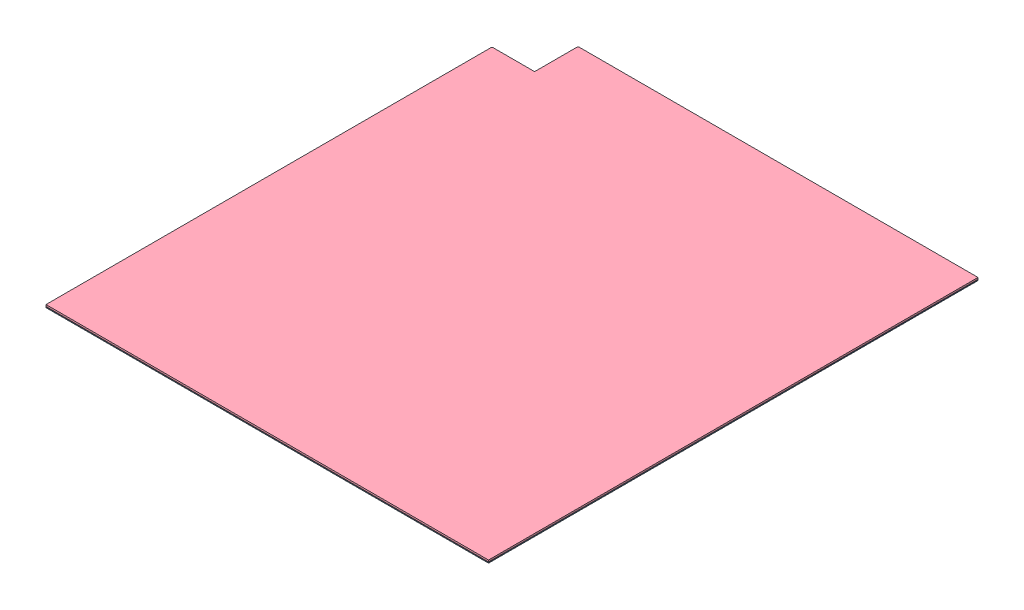
SolidWorks assembly GE-20057, configuration Default. Lengths in mm.
Overall size (1616.07 10.06 1787.53).
7 component instances, 5 part files, 18 mates.
Components (placement in the parent):
- GE-20055-1: GE-20055 [Default] at origin size (1616.07 2.92 593.72)
- Carpet Tape _ 63.625-1: Carpet Tape _ 63.625 [Default] at (808.0375 2.921 -25.4) x (0 0 1) z (-1 0 0) size (50.8 0.79 1616.07)
- Carpet Tape _ 57.375-1: Carpet Tape _ 57.375 [Default] at (887.4125 2.921 -568.325) x (0 0 1) z (-1 0 0) size (50.8 0.79 1457.33)
- GE-20057 - 01-1: GE-20057 - 01 [Default] at (0 3.7147 1193.8) size (1616.07 6.35 1787.53)
- GE-20056-1: GE-20056 [Default] at (0 0 1193.8) size (1616.07 2.92 1193.8)
- Carpet Tape _ 63.625-2: Carpet Tape _ 63.625 [Default] at (808.0375 2.921 25.4) x (0 0 -1) z (1 0 0) size (50.8 0.79 1616.07)
- Carpet Tape _ 63.625-4: Carpet Tape _ 63.625 [Default] at (808.0375 2.921 1168.4) x (0 0 1) z (-1 0 0) size (50.8 0.79 1616.07)
Mates (geometry in assembly coordinates):
- Coincident1: coincident anti-aligned: plane of GE-20055-1 through (3.175 2.921 -431.8) normal (0 1 0); plane of Carpet Tape _ 63.625-1 through (808.0375 2.921 -25.4) normal (0 -1 0)
- Coincident2: coincident aligned: plane of GE-20055-1 through (0 2.921 0) normal (0 0 1); plane of Carpet Tape _ 63.625-1 through (1616.075 3.7147 0) normal (0 0 1)
- Coincident3: coincident aligned: plane of GE-20055-1 through (1616.075 2.921 0) normal (1 0 0); plane of Carpet Tape _ 63.625-1 through (1616.075 3.7147 -50.8) normal (1 0 0)
- Coincident4: coincident anti-aligned: plane of GE-20055-1 through (3.175 2.921 -431.8) normal (0 1 0); plane of Carpet Tape _ 57.375-1 through (887.4125 2.921 -568.325) normal (0 -1 0)
- Coincident5: coincident aligned: plane of GE-20055-1 through (158.75 2.921 -593.725) normal (0 0 -1); plane of Carpet Tape _ 57.375-1 through (1616.075 3.7147 -593.725) normal (0 0 -1)
- Coincident6: coincident: line of GE-20055-1 through (158.75 2.921 -593.725) axis (0 -1 0); plane of Carpet Tape _ 57.375-1 through (158.75 3.7147 -593.725) normal (-1 0 0)
- Coincident7: coincident anti-aligned: plane of Carpet Tape _ 57.375-1 through (887.4125 3.7147 -568.325) normal (0 1 0); plane of GE-20057 - 01-1 through (3.175 3.7147 -1625.6) normal (0 -1 0)
- Coincident8: coincident aligned: plane of GE-20055-1 through (0 2.921 0) normal (-1 0 0); plane of GE-20057 - 01-1 through (0 10.0648 0) normal (-1 0 0)
- Coincident9: coincident aligned: plane of GE-20056-1 through (0 2.921 1193.8) normal (0 0 1); plane of GE-20057 - 01-1 through (0 10.0648 1193.8) normal (0 0 1)
- Coincident10: coincident aligned: plane of GE-20055-1 through (0 2.921 0) normal (-1 0 0); plane of GE-20056-1 through (0 2.921 1193.8) normal (-1 0 0)
- Coincident11: coincident anti-aligned: plane of GE-20055-1 through (0 2.921 0) normal (0 0 1); plane of GE-20056-1 through (0 2.921 0) normal (0 0 -1)
- Coincident12: coincident aligned: plane of GE-20055-1 through (3.175 0 -431.8) normal (0 -1 0); plane of GE-20056-1 through (0 0 1193.8) normal (0 -1 0)
- Coincident13: coincident anti-aligned: plane of GE-20056-1 through (0 2.921 1193.8) normal (0 1 0); plane of Carpet Tape _ 63.625-2 through (808.0375 2.921 25.4) normal (0 -1 0)
- Coincident15: coincident aligned: plane of GE-20056-1 through (0 2.921 0) normal (0 0 -1); plane of Carpet Tape _ 63.625-2 through (0 3.7147 0) normal (0 0 -1)
- Coincident16: coincident aligned: plane of GE-20056-1 through (0 2.921 1193.8) normal (-1 0 0); plane of Carpet Tape _ 63.625-2 through (0 3.7147 50.8) normal (-1 0 0)
- Coincident17: coincident anti-aligned: plane of GE-20056-1 through (0 2.921 1193.8) normal (0 1 0); plane of Carpet Tape _ 63.625-4 through (808.0375 2.921 1168.4) normal (0 -1 0)
- Coincident18: coincident aligned: plane of GE-20056-1 through (0 2.921 1193.8) normal (0 0 1); plane of Carpet Tape _ 63.625-4 through (1616.075 3.7147 1193.8) normal (0 0 1)
- Coincident19: coincident aligned: plane of GE-20056-1 through (1616.075 2.921 1193.8) normal (1 0 0); plane of Carpet Tape _ 63.625-4 through (1616.075 3.7147 1143) normal (1 0 0)
